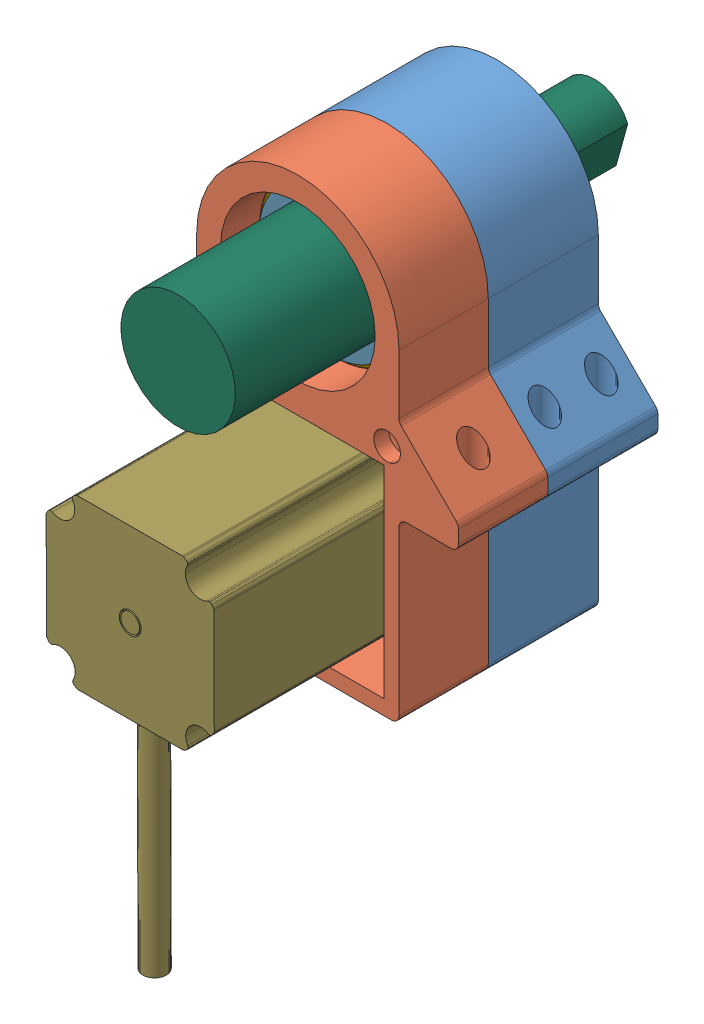
SolidWorks assembly Assemblage1, configuration Défaut. Lengths in mm.
Overall size (108 209.55 155.77).
22 component instances, 19 part files, 18 mates.
Components (placement in the parent):
- Nema23ColumnHolderPart2V2-1: Nema23ColumnHolderPart2V2 [Défaut] at origin size (108 143 37)
- Nema23ColumnHolderv2-1: Nema23ColumnHolderv2 [Défaut] at (0 0 42) size (108 143 30)
- bearing_6806-2nse-1: bearing_6806-2nse [Default] at (0 0 3.5) x (0 0 1) z (-0.944955 0.327201 0) size (7 42 42)
  - bearing_6806-2nse_01-1: bearing_6806-2nse_01 [Default] at origin size (7 34 34)
  - bearing_6806-2nse_02-1: bearing_6806-2nse_02 [Default] at origin size (7 42 42)
  - bearing_6806-2nse_03-1: bearing_6806-2nse_03 [Default] at origin size (4.2 40.06 40.13)
  - bearing_6806-2nse_04-1: bearing_6806-2nse_04 [Default] at origin size (0.5 39.6 39.6)
  - bearing_6806-2nse_05-1: bearing_6806-2nse_05 [Default] at origin size (0.5 39.6 39.6)
- bearing_6808nse-1: bearing_6808nse [Default] at (0 0 45.5) x (0 0 -1) z (0.89707 0.441888 0) size (7 52 52)
  - bearing_6808nse_01-1: bearing_6808nse_01 [Default] at origin size (7 44 44)
  - bearing_6808nse_02-1: bearing_6808nse_02 [Default] at origin size (7 52 52)
  - bearing_6808nse_03-1: bearing_6808nse_03 [Default] at origin size (4.2 50.2 50.2)
  - bearing_6808nse_04-1: bearing_6808nse_04 [Default] at origin size (0.5 49.6 49.6)
- stp-mtrac-23078-1: stp-mtrac-23078 [Default] at (-0.35 -68.5743 42) x (0.999996 0.002965 0) z (0 0 -1) size (56.41 132.6 96.03)
- Bearing6806FordAdapter-1: Bearing6806FordAdapter [Défaut] at (0 0 7) x (-0.963659 0.267134 0) z (0 0 -1) size (38 38 10)
- Bearing6808FordAdapter-1: Bearing6808FordAdapter [Défaut] at (0 0 49) x (-0.440028 0.897984 0) z (0 0 -1) size (48 48 9)
- FordColumnPlaceholder-1: FordColumnPlaceholder [Défaut] at (0 0 32.2366) x (-0.963659 0.267134 0) z (0 0 -1) size (38.5 38.5 140)
- FordPulley36TBoltHTD5MSplit-1: FordPulley36TBoltHTD5MSplit [Défaut] at (5.0774 33.2403 13.8133) x (0.963659 -0.267134 0) z (0 0 1) size (59.3 59.3 19)
- a9-12-5m15-1: a9-12-5m15 [Default] at (-0.35 -68.5743 14.5425) x (0 0 1) z (-0.583711 -0.811961 0) size (26.4 23 23)
  - a9-12-5m15_01-1: a9-12-5m15_01 [Default] at origin size (26 17.96 17.96)
  - a9-12-5m15_02-1: a9-12-5m15_02 [Default] at origin size (1.4 23 23)
  - a9-12-5m15_03-1: a9-12-5m15_03 [Default] at origin size (1.4 23 23)
Mates (geometry in assembly coordinates):
- Coaxiale1: concentric aligned: circle of Nema23ColumnHolderPart2V2-1; circle of Nema23ColumnHolderv2-1
- Coïncidente2: coincident aligned: circle of Nema23ColumnHolderPart2V2-1; circle of Nema23ColumnHolderv2-1
- Coïncidente7: coincident anti-aligned: plane of Nema23ColumnHolderv2-1 through (0 0 42) normal (0 0 1); plane of stp-mtrac-23078-1 through (-28.6335 -40.458 42) normal (0 0 -1)
- Coaxiale12: concentric anti-aligned: cylinder of bearing_6806-2nse-1/bearing_6806-2nse_01-1 through (0 0 3.5) axis (0 0 -1) radius 15; cylinder of Bearing6806FordAdapter-1 through (0 0 0) axis (0 0 1) radius 15
- Coïncidente9: coincident anti-aligned: circle of bearing_6806-2nse-1/bearing_6806-2nse_01-1; plane of Bearing6806FordAdapter-1 through (0 0 7) normal (0 0 -1)
- Coaxiale13: concentric aligned: cylinder of bearing_6808nse-1/bearing_6808nse_01-1 through (0 0 45.5) axis (0 0 1) radius 20; cylinder of Bearing6808FordAdapter-1 through (0 0 42) axis (0 0 1) radius 20
- Coïncidente11: coincident aligned: circle of bearing_6808nse-1/bearing_6808nse_01-1; plane of Bearing6808FordAdapter-1 through (0 0 49) normal (0 0 -1)
- Coïncidente12: coincident anti-aligned: plane of Nema23ColumnHolderv2-1 through (0 0 42) normal (0 0 1); circle of bearing_6808nse-1/bearing_6808nse_02-1
- Coaxiale14: concentric anti-aligned: cylinder of Nema23ColumnHolderv2-1 through (0 0 62) axis (0 0 -1) radius 26; cylinder of bearing_6808nse-1/bearing_6808nse_02-1 through (0 0 45.5) axis (0 0 1) radius 26
- Coaxiale15: concentric aligned: cylinder of Nema23ColumnHolderPart2V2-1 through (0 0 7) axis (0 0 -1) radius 21.5; cylinder of bearing_6806-2nse-1/bearing_6806-2nse_02-1 through (0 0 3.5) axis (0 0 -1) radius 21
- Coïncidente13: coincident aligned: plane of Nema23ColumnHolderPart2V2-1 through (0 0 0) normal (0 0 1); circle of bearing_6806-2nse-1/bearing_6806-2nse_02-1
- Coaxiale16: concentric anti-aligned: cylinder of Bearing6808FordAdapter-1 through (0 0 42) axis (0 0 1) radius 19.25; cylinder of FordColumnPlaceholder-1 through (0 0 102.2366) axis (0 0 -1) radius 19.25
- Coïncidente14: coincident anti-aligned: plane of Bearing6806FordAdapter-1 through (9.1548 -2.5378 0) normal (-0.963659 0.267134 0); plane of FordColumnPlaceholder-1 through (9.1548 -2.5378 -37.7634) normal (0.963659 -0.267134 0)
- Coïncidente18: coincident: line of Nema23ColumnHolderv2-1 through (25.75 -51.5 42) axis (0 1 0); point of stp-mtrac-23078-1
- Coïncidente19: coincident: line of Nema23ColumnHolderv2-1 through (-21.25 -98.5 42) axis (0 1 0); point of stp-mtrac-23078-1
- Coïncidente20: coincident anti-aligned: plane of FordColumnPlaceholder-1 through (-9.1548 2.5378 -37.7634) normal (-0.963659 0.267134 0); plane of FordPulley36TBoltHTD5MSplit-1 through (-0.2355 34.7131 10.8947) normal (0.963659 -0.267134 0)
- Coaxiale17: concentric aligned: cylinder of FordColumnPlaceholder-1 through (0 0 -37.7634) axis (0 0 1) radius 12; cylinder of FordPulley36TBoltHTD5MSplit-1 through (0 0 10.8947) axis (0 0 1) radius 12
- Coaxiale18: concentric anti-aligned: cylinder of stp-mtrac-23078-1 through (-0.35 -68.5743 32) axis (0 0 -1) radius 2.675; cylinder of a9-12-5m15-1/a9-12-5m15_01-1 through (-0.35 -68.5743 40.5425) axis (0 0 1) radius 3
